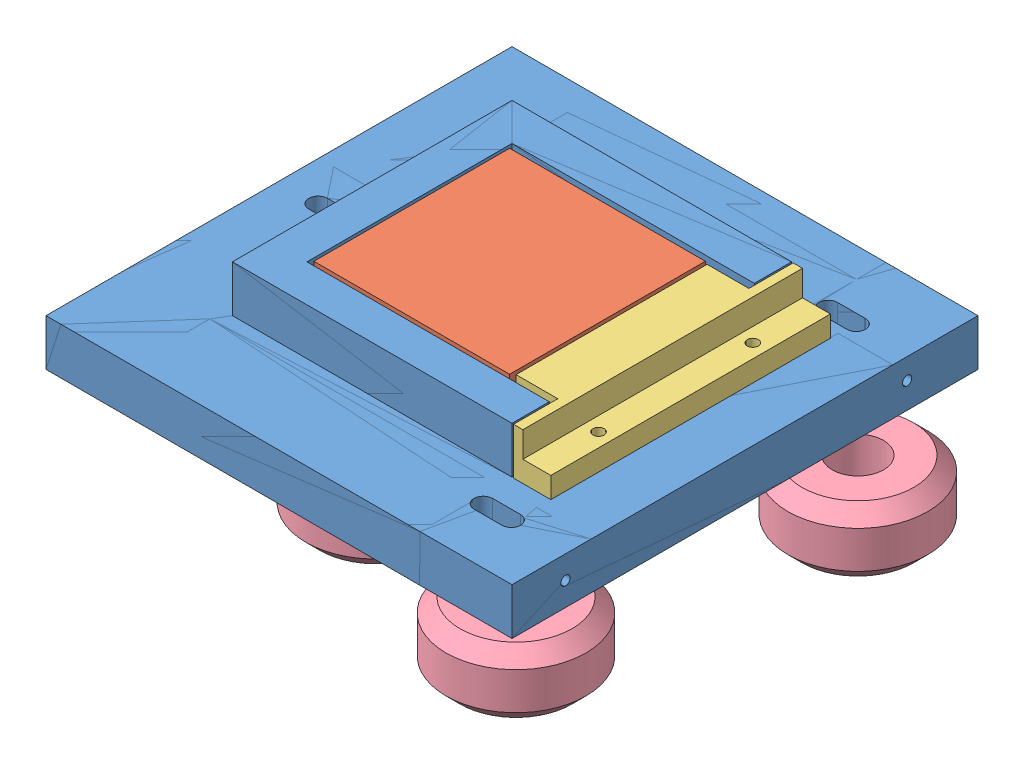
SolidWorks assembly mountassemblybasic, configuration Default. Lengths in mm.
Overall size (102.02 67.49 102.72).
7 component instances, 4 part files, 0 mates.
Components (placement in the parent):
- universalmount-1: universalmount [Default] at (-11.5343 43.3988 108.5117) size (100 20 100)
- mountingplateformount-1: mountingplateformount [Default] at (-11.8849 53.412 108.6755) x (0 1 0) z (0 0 -1) size (10 49 49)
- mountlock-1: mountlock [Default] at (24.6753 53.4721 134.8032) size (16.96 10 60)
- wheel-1: wheel [Default] at (25.4852 27.383 71.308) x (1 0 0) z (0 -1 0) size (30 30 14)
- wheel-2: wheel [Default] at (-45.9217 -4.0179 103.337) x (1 0 0) z (0 1 0) size (30 30 14)
- wheel-3: wheel [Default] at (24.8468 23.157 144.0329) x (1 0 0) z (0 1 0) size (30 30 14)
- universalmount-2: universalmount [Default] at (-11.5343 43.3988 108.5117) size (100 20 100)
